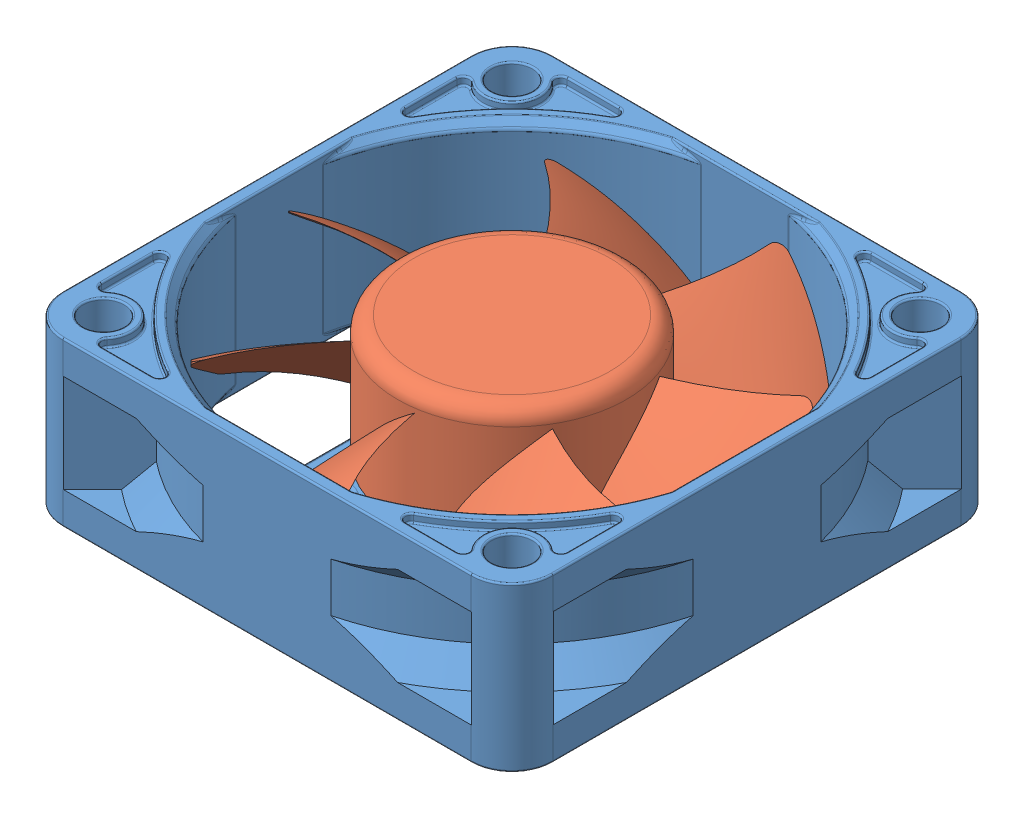
SolidWorks assembly Fan_Assembly, configuration По умолчанию. Lengths in mm.
Overall size (62.65 20.13 63.06).
2 component instances, 2 part files, 2 mates.
Components (placement in the parent):
- Fan_Case-1: Fan_Case [По умолчанию] at origin size (60 20.13 60)
- Fan-1: Fan [По умолчанию] at (0 -5 0) size (62.65 17 63.06)
Mates (geometry in assembly coordinates):
- Концентричный1: concentric anti-aligned: cylinder of Fan_Case-1 through (0 5 0) axis (0 -1 0) radius 2; cylinder of Fan-1 through (0 -7 0) axis (0 1 0) radius 2
- Совпадение2: coincident aligned: plane of Fan_Case-1 through (0 10 0) normal (0 1 0); plane of Fan-1 through (0 10 0) normal (0 1 0)
